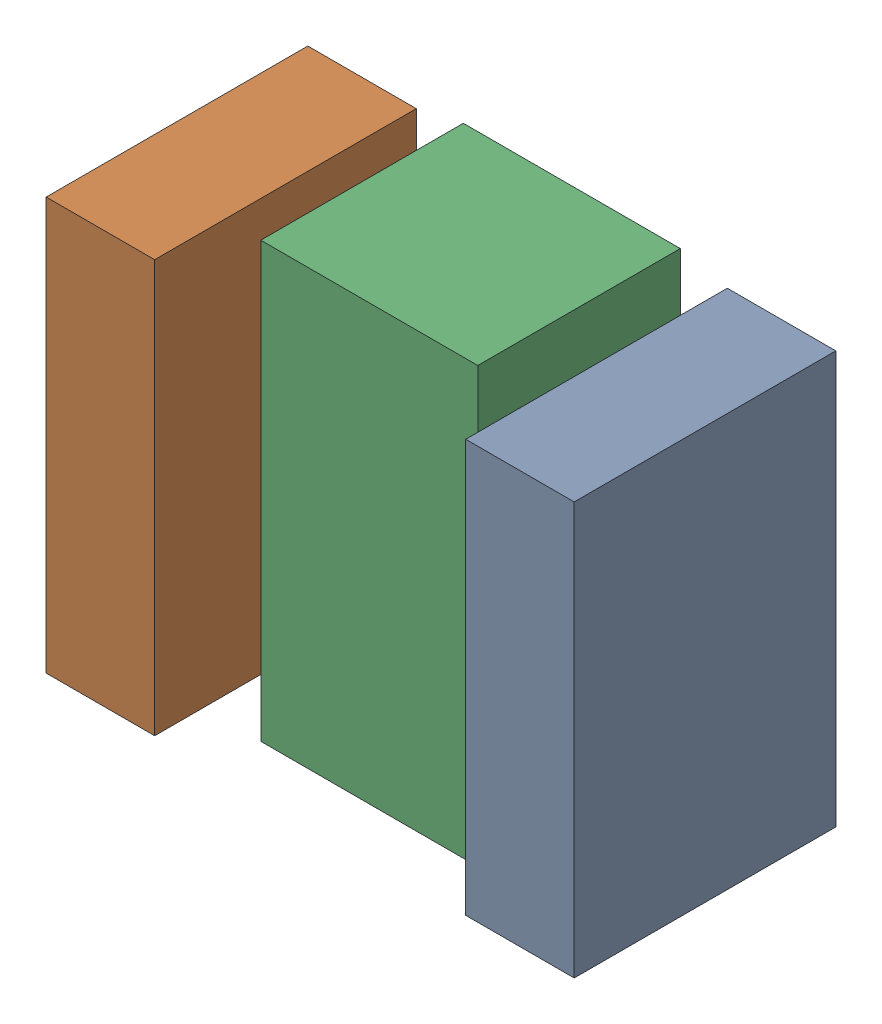
SolidWorks assembly C11_Motor_5Kanaloa_v2.0.0_Motor, configuration Default. Lengths in mm.
Overall size (3.65 3 1.81).
6 component instances, 2 part files, 0 mates.
Components (placement in the parent):
- 334788400-1: 334788400 [Default] at (121.549 81.026 0) size (0.75 2.85 1.81)
  - Extruded_5-1: Extruded_5 [Default] at origin size (0.75 2.85 1.81)
- 334788400-2: 334788400 [Default] at (118.649 81.026 0) size (0.75 2.85 1.81)
  - Extruded_5-1: Extruded_5 [Default] at origin size (0.75 2.85 1.81)
- 334788656-1: 334788656 [Default] at (120.099 81.026 0) size (1.5 3 1.4)
  - Extruded_1-1: Extruded_1 [Default] at origin size (1.5 3 1.4)
